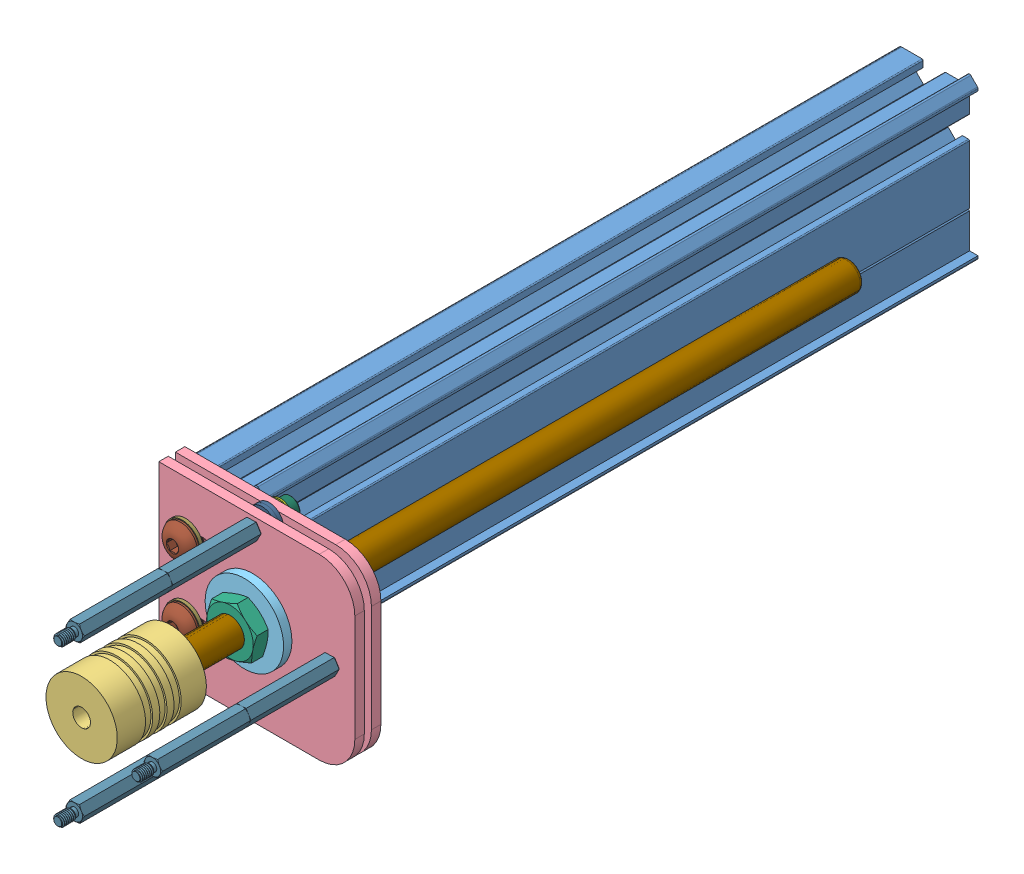
SolidWorks assembly S2_Zaxis_500, configuration Default. Lengths in mm.
Overall size (63.97 54.77 264.94).
47 component instances, 18 part files, 97 mates.
Components (placement in the parent):
- 25142-07-1: 25142-07 [Default] at origin size (22.38 45.94 200)
- 26016-01-1: 26016-01 [Default] at (-6.4 10 -90) x (0 1 0) z (0 0 1) size (10 1.6 15)
- 26016-01-2: 26016-01 [Default] at (-6.4 10 29.5) x (0 1 0) z (0 0 1) size (10 1.6 15)
- 26016-01-3: 26016-01 [Default] at (-6.4 -10 -90) x (0 1 0) z (0 0 1) size (10 1.6 15)
- 26016-01-4: 26016-01 [Default] at (-6.4 -10 29.5) x (0 1 0) z (0 0 1) size (10 1.6 15)
- 25772-02-1: 25772-02 [Default] at (18.85 0 157.9705) x (-0.547932 -0.836523 0) z (0 0 -1) size (20 20 25)
- z-mount_plates-1: z-mount_plates [Default] at (2.5 0 102.6568) size (55 50 2.66)
- z-mount_plates-2: z-mount_plates [Default] at (2.5 0 107.3137) size (55 50 2.66)
- 30169-01-1: 30169-01 [Default] at (18.85 0 112.3137) x (1 -0.000065 0) z (0 0 -1) size (25 25 7)
- 90695A040-1: 90695A040 [Default] at (18.85 0 114.3137) x (-0.665272 -0.746601 0) z (0.746601 -0.665272 0) size (13 4.47 15.01)
- 90695A040-2: 90695A040 [Default] at (18.85 0 103.3137) x (0.698752 0.715364 0) z (0.715364 -0.698752 0) size (13 4.47 15.01)
- 25287-03-1: 25287-03 [Default] at (18.85 21.9203 102.2068) x (0.999998 -0.002105 0) z (0 0 -1) size (7 7 0.45)
- 25287-03-2: 25287-03 [Default] at (40.7703 0 102.2068) x (0.999998 -0.002105 0) z (0 0 -1) size (7 7 0.45)
- 25287-03-3: 25287-03 [Default] at (18.85 -21.9203 102.2068) x (0.999998 -0.002105 0) z (0 0 -1) size (7 7 0.45)
- z-axis shim-1: z-axis shim [Default] at (0 0 100) x (0 1 0) z (0 0 1) size (40 20 2.66)
- SM-H05-1: SM-H05 [Default] at (18.85 0 -57.5045) x (0.600975 0.799267 0) z (0 0 1) size (8 8 200.01)
- 492-1101-ND-1: 492-1101-ND [Default] at (18.85 21.9203 106.3137) x (0.918344 -0.395784 0) z (0 0 1) size (8 8 1)
- 492-1101-ND-2: 492-1101-ND [Default] at (40.7703 0 106.3137) x (1 -0.000065 0) z (0 0 1) size (8 8 1)
- 492-1101-ND-3: 492-1101-ND [Default] at (18.85 -21.9203 106.3137) x (1 -0.000065 0) z (0 0 1) size (8 8 1)
- 91239A233-1: 91239A233 [Default] at (0 -10 90.8705) x (-0.018677 0.999826 0) z (0 0 -1) size (9.5 9.5 22.91)
- 25287-02-1: 25287-02 [Default] at (0 -10 110.8705) x (-0.018677 0.999826 0) z (0 0 1) size (10 10 0.9)
- 91239A233-2: 91239A233 [Default] at (0 10 90.8705) x (-0.018677 0.999826 0) z (0 0 -1) size (9.5 9.5 22.91)
- 25287-02-2: 25287-02 [Default] at (0 10 110.8705) x (-0.018677 0.999826 0) z (0 0 1) size (10 10 0.9)
- PSM5-01MM-1: PSM5-01MM [Default] at (0 10 106.3137) x (-0.941883 0.335942 0) z (0 0 -1) size (10 10 1)
- PSM5-01MM-2: PSM5-01MM [Default] at (0 -10 105.3137) x (1 -0.000065 0) z (0 0 1) size (10 10 1)
- PSBS-50-1: PSBS-50 [Default] at (18.85 21.9203 149.8205) x (0 0 1) z (0.847933 0.530103 0) size (54.97 5.2 4.5)
- PSBS-50-2: PSBS-50 [Default] at (18.85 -21.9203 149.8205) x (0 0 1) z (0.847933 0.530103 0) size (54.97 5.2 4.5)
- PSBS-50-3: PSBS-50 [Default] at (40.7703 0 149.8205) x (0 0 1) z (0.847933 0.530103 0) size (54.97 5.2 4.5)
- 25285-10-1: 25285-10 [Default] at (18.85 21.9203 114.2068) x (1 -0.000065 0) z (0 0 1) size (5.5 5.5 15.14)
- 25285-10-2: 25285-10 [Default] at (40.7703 0 114.2068) x (1 -0.000065 0) z (0 0 1) size (5.5 5.5 15.14)
- 25285-10-3: 25285-10 [Default] at (18.85 -21.9203 114.2068) x (1 -0.000065 0) z (0 0 1) size (5.5 5.5 15.14)
- PSM5-01MM-3: PSM5-01MM [Default] at (0 10 106.3137) x (-0.91721 -0.398405 0) z (0 0 1) size (10 10 1)
- PSM5-01MM-4: PSM5-01MM [Default] at (0 -10 106.3137) x (-0.91721 -0.398405 0) z (0 0 1) size (10 10 1)
- 492-1101-ND-4: 492-1101-ND [Default] at (18.85 21.9203 105.3137) x (0.69206 -0.72184 0) z (0 0 1) size (8 8 1)
- 492-1101-ND-5: 492-1101-ND [Default] at (40.7703 0 106.3137) x (0.914241 0.405172 0) z (0 0 -1) size (8 8 1)
- 492-1101-ND-6: 492-1101-ND [Default] at (18.85 -21.9203 106.3137) x (0.914241 0.405172 0) z (0 0 -1) size (8 8 1)
- 91290A272-1: 91290A272 [Default] at (152.9795 421.0336 165.2742) x (-0.956811 0.027475 0.289409) z (-0.289409 0.004064 -0.957197) (suppressed, hidden)
- 91290A272-6: 91290A272 [Default] at (88.3739 418.8513 182.2519) x (-0.956811 0.027475 0.289409) z (-0.289409 0.004064 -0.957197) (suppressed, hidden)
- 9714K630-1: 9714K630 [Default] at (18.85 0 105.2817) x (-0.456655 -0.889644 0) z (-0.889644 0.456655 0) size (30.59 5.44 32.38)
- 25287-02-3: 25287-02 [Default] at (-13.56 -10 -90) x (0 0.90826 -0.418406) z (-1 0 0) size (10 10 0.9)
- 25286-01-1: 25286-01 [Default] at (-3.56 -10 -90) x (0 0.955266 -0.295749) z (1 0 0) size (9.5 9.5 12.91)
- 25287-02-4: 25287-02 [Default] at (-13.56 -10 29.5) x (0 0.90826 -0.418406) z (-1 0 0) size (10 10 0.9)
- 25286-01-2: 25286-01 [Default] at (-3.56 -10 29.5) x (0 0.955266 -0.295749) z (1 0 0) size (9.5 9.5 12.91)
- 25287-02-5: 25287-02 [Default] at (-13.56 10 -90) x (0 0.90826 -0.418406) z (-1 0 0) size (10 10 0.9)
- 25286-01-3: 25286-01 [Default] at (-3.56 10 -90) x (0 0.955266 -0.295749) z (1 0 0) size (9.5 9.5 12.91)
- 25287-02-6: 25287-02 [Default] at (-13.56 10 29.5) x (0 0.90826 -0.418406) z (-1 0 0) size (10 10 0.9)
- 25286-01-4: 25286-01 [Default] at (-3.56 10 29.5) x (0 0.955266 -0.295749) z (1 0 0) size (9.5 9.5 12.91)
Mates (geometry in assembly coordinates):
- Coincident51: coincident anti-aligned: plane of 25142-07-1 through (-8 -16 0) normal (1 0 0); plane of 26016-01-3 through (-8 -10 -90) normal (-1 0 0)
- Coincident52: coincident anti-aligned: plane of 25142-07-1 through (-8 -16 0) normal (1 0 0); plane of 26016-01-4 through (-8 -10 29.5) normal (-1 0 0)
- Coincident53: coincident anti-aligned: plane of 25142-07-1 through (-8 13 0) normal (1 0 0); plane of 26016-01-2 through (-8 10 29.5) normal (-1 0 0)
- Coincident54: coincident anti-aligned: plane of 25142-07-1 through (-8 13 0) normal (1 0 0); plane of 26016-01-1 through (-8 10 -90) normal (-1 0 0)
- Coincident55: coincident aligned: plane of 26016-01-1 through (-6.4 15 -97.5) normal (0 0 -1); plane of 26016-01-3 through (-6.4 -5 -97.5) normal (0 0 -1)
- Coincident57: coincident aligned: plane of 25142-07-1 through (0 10 0) normal (0 1 0); plane of 26016-01-1
- Coincident58: coincident aligned: plane of 25142-07-1 through (0 10 0) normal (0 1 0); plane of 26016-01-2
- Coincident59: coincident aligned: plane of 25142-07-1 through (0 -10 0) normal (0 1 0); plane of 26016-01-3
- Coincident60: coincident aligned: plane of 25142-07-1 through (0 -10 0) normal (0 1 0); plane of 26016-01-4
- Distance1: distance = 2.5 mm aligned: plane of 25142-07-1 through (0.3057 0.8501 -100) normal (0 0 -1); plane of 26016-01-1 through (-6.4 15 -97.5) normal (0 0 -1)
- Concentric44: concentric anti-aligned: cylinder of z-mount_plates-2 through (18.85 0 107.3137) axis (0 0 1) radius 11; cylinder of 30169-01-1 through (18.85 0 112.3137) axis (0 0 -1) radius 11
- Concentric45: concentric anti-aligned: cylinder of z-mount_plates-2 through (0 -10 107.3137) axis (0 0 1) radius 2.75; cylinder of 91239A233-1 through (0 -10 113.6205) axis (0 0 -1) radius 4.75
- Concentric46: concentric anti-aligned: cylinder of z-mount_plates-2 through (0 10 107.3137) axis (0 0 1) radius 2.75; cylinder of 91239A233-2 through (0 10 113.6205) axis (0 0 -1) radius 4.75
- Concentric47: concentric anti-aligned: cylinder of 91239A233-2 through (0 10 113.6205) axis (0 0 -1) radius 4.75; cylinder of 25287-02-2 through (0 10 109.9705) axis (0 0 1) radius 5
- Concentric48: concentric anti-aligned: cylinder of 91239A233-1 through (0 -10 113.6205) axis (0 0 -1) radius 4.75; cylinder of 25287-02-1 through (0 -10 109.9705) axis (0 0 1) radius 5
- Concentric49: concentric aligned: cylinder of z-mount_plates-1 through (0 -10 102.6568) axis (0 0 1) radius 2.75; cylinder of z-mount_plates-2 through (0 -10 107.3137) axis (0 0 1) radius 2.75
- Concentric50: concentric aligned: cylinder of z-mount_plates-1 through (0 10 102.6568) axis (0 0 1) radius 2.75; cylinder of z-mount_plates-2 through (0 10 107.3137) axis (0 0 1) radius 2.75
- Concentric51: concentric aligned: cylinder of PSM5-01MM-2 through (0 -10 105.3137) axis (0 0 1) radius 5; cylinder of PSM5-01MM-4 through (0 -10 106.3137) axis (0 0 1) radius 5
- Concentric52: concentric anti-aligned: cylinder of PSM5-01MM-1 through (0 10 106.3137) axis (0 0 -1) radius 5; cylinder of PSM5-01MM-3 through (0 10 106.3137) axis (0 0 1) radius 5
- Concentric53: concentric anti-aligned: cylinder of 492-1101-ND-3 through (18.85 -21.9203 106.3137) axis (0 0 1) radius 4; cylinder of 492-1101-ND-6 through (18.85 -21.9203 106.3137) axis (0 0 -1) radius 4
- Concentric54: concentric anti-aligned: cylinder of 492-1101-ND-2 through (40.7703 0 106.3137) axis (0 0 1) radius 4; cylinder of 492-1101-ND-5 through (40.7703 0 106.3137) axis (0 0 -1) radius 4
- Concentric55: concentric aligned: cylinder of 492-1101-ND-1 through (18.85 21.9203 106.3137) axis (0 0 1) radius 4; cylinder of 492-1101-ND-4 through (18.85 21.9203 105.3137) axis (0 0 1) radius 4
- Concentric56: concentric anti-aligned: cylinder of 25287-03-3 through (18.85 -21.9203 102.6568) axis (0 0 -1) radius 3.5; cylinder of 25285-10-3 through (18.85 -21.9203 99.2068) axis (0 0 1) radius 2.75
- Concentric57: concentric anti-aligned: cylinder of 25287-03-2 through (40.7703 0 102.6568) axis (0 0 -1) radius 3.5; cylinder of 25285-10-2 through (40.7703 0 99.2068) axis (0 0 1) radius 2.75
- Concentric58: concentric anti-aligned: cylinder of 25287-03-1 through (18.85 21.9203 102.6568) axis (0 0 -1) radius 3.5; cylinder of 25285-10-1 through (18.85 21.9203 99.2068) axis (0 0 1) radius 2.75
- Concentric59: concentric anti-aligned: cylinder of 25285-10-2 through (40.7703 0 99.2068) axis (0 0 1) radius 2.75; cylinder of 492-1101-ND-5 through (40.7703 0 106.3137) axis (0 0 -1) radius 1.5
- Concentric60: concentric aligned: cylinder of 25285-10-1 through (18.85 21.9203 99.2068) axis (0 0 1) radius 2.75; cylinder of 492-1101-ND-4 through (18.85 21.9203 105.3137) axis (0 0 1) radius 1.5
- Concentric61: concentric anti-aligned: cylinder of 25285-10-3 through (18.85 -21.9203 99.2068) axis (0 0 1) radius 2.75; cylinder of 492-1101-ND-6 through (18.85 -21.9203 106.3137) axis (0 0 -1) radius 1.5
- Coincident64: coincident anti-aligned: plane of 25287-03-3 through (18.85 -21.9203 102.2068) normal (0 0 -1); plane of 25285-10-3 through (18.85 -21.9203 102.2068) normal (0 0 1)
- Coincident65: coincident anti-aligned: plane of 25287-03-2 through (40.7703 0 102.2068) normal (0 0 -1); plane of 25285-10-2 through (40.7703 0 102.2068) normal (0 0 1)
- Coincident66: coincident anti-aligned: plane of 25287-03-1 through (18.85 21.9203 102.2068) normal (0 0 -1); plane of 25285-10-1 through (18.85 21.9203 102.2068) normal (0 0 1)
- Concentric62: concentric aligned: cylinder of z-mount_plates-1 through (18.85 0 102.6568) axis (0 0 1) radius 11; circle of 90695A040-2
- Concentric63: concentric aligned: cylinder of z-mount_plates-2 through (18.85 0 107.3137) axis (0 0 1) radius 11; circle of 90695A040-1
- Concentric64: concentric anti-aligned: cylinder of z-mount_plates-2 through (18.85 -21.9203 107.3137) axis (0 0 1) radius 1.75; cylinder of PSBS-50-2 through (18.85 -21.9203 149.8205) axis (0 0 -1) radius 1.1727
- Concentric65: concentric anti-aligned: cylinder of z-mount_plates-2 through (40.7703 0 107.3137) axis (0 0 1) radius 1.75; cylinder of PSBS-50-3 through (40.7703 0 149.8205) axis (0 0 -1) radius 1.1727
- Concentric66: concentric anti-aligned: cylinder of z-mount_plates-2 through (18.85 21.9203 107.3137) axis (0 0 1) radius 1.75; cylinder of PSBS-50-1 through (18.85 21.9203 149.8205) axis (0 0 -1) radius 1.1727
- Concentric67: concentric anti-aligned: cylinder of 30169-01-1 through (18.85 0 112.3137) axis (0 0 -1) radius 4; cylinder of SM-H05-1 through (18.85 0 -57.5045) axis (0 0 1) radius 4
- Coincident67: coincident anti-aligned: plane of 492-1101-ND-2 through (40.7703 0 106.3137) normal (0 0 -1); plane of 492-1101-ND-5 through (40.7703 0 106.3137) normal (0 0 1)
- Coincident68: coincident anti-aligned: plane of 492-1101-ND-3 through (18.85 -21.9203 106.3137) normal (0 0 -1); plane of 492-1101-ND-6 through (18.85 -21.9203 106.3137) normal (0 0 1)
- Coincident69: coincident anti-aligned: plane of PSM5-01MM-1 through (0 10 106.3137) normal (0 0 1); plane of PSM5-01MM-3 through (0 10 106.3137) normal (0 0 -1)
- Coincident70: coincident anti-aligned: plane of 492-1101-ND-1 through (18.85 21.9203 106.3137) normal (0 0 -1); plane of 492-1101-ND-4 through (18.85 21.9203 106.3137) normal (0 0 1)
- Coincident71: coincident anti-aligned: plane of PSM5-01MM-2 through (0 -10 106.3137) normal (0 0 1); plane of PSM5-01MM-4 through (0 -10 106.3137) normal (0 0 -1)
- Concentric68: concentric aligned: cylinder of 25142-07-1 through (0 -10 100) axis (0 0 -1) radius 2.5; cylinder of z-axis shim-1 through (0 -10 102.6568) axis (0 0 -1) radius 2.75
- Concentric69: concentric aligned: cylinder of 25142-07-1 through (0 10 100) axis (0 0 -1) radius 2.5; cylinder of z-axis shim-1 through (0 10 102.6568) axis (0 0 -1) radius 2.75
- Coincident72: coincident anti-aligned: plane of 25142-07-1 through (0 0 100) normal (0 0 1); plane of z-axis shim-1 through (-0.1617 0 100) normal (0 0 -1)
- Coincident73: coincident anti-aligned: plane of 91239A233-1 through (0 -10 110.8705) normal (0 0 -1); plane of 25287-02-1 through (0 -10 110.8705) normal (0 0 1)
- Coincident74: coincident anti-aligned: plane of 91239A233-2 through (0 10 110.8705) normal (0 0 -1); plane of 25287-02-2 through (0 10 110.8705) normal (0 0 1)
- Coincident75: coincident anti-aligned: plane of z-mount_plates-2 through (20 0 109.9705) normal (0 0 1); plane of 25287-02-2 through (0 10 109.9705) normal (0 0 -1)
- Coincident76: coincident anti-aligned: plane of z-mount_plates-2 through (20 0 109.9705) normal (0 0 1); plane of 25287-02-1 through (0 -10 109.9705) normal (0 0 -1)
- Concentric70: concentric anti-aligned: cylinder of 25772-02-1 through (18.85 0 157.9705) axis (0 0 -1) radius 2.5; cylinder of SM-H05-1 through (18.85 0 -57.5045) axis (0 0 1) radius 4
- Coincident77: coincident anti-aligned: plane of z-mount_plates-2 through (20 0 109.9705) normal (0 0 1); plane of PSBS-50-2 through (17.8069 -23.8832 109.9705) normal (0 0 -1)
- Coincident78: coincident anti-aligned: plane of z-mount_plates-2 through (20 0 109.9705) normal (0 0 1); plane of PSBS-50-3 through (39.7272 -1.9629 109.9705) normal (0 0 -1)
- Coincident79: coincident anti-aligned: plane of z-mount_plates-2 through (20 0 109.9705) normal (0 0 1); plane of PSBS-50-1 through (17.8069 19.9574 109.9705) normal (0 0 -1)
- Coincident80: coincident anti-aligned: plane of z-mount_plates-2 through (20 0 107.3137) normal (0 0 -1); plane of 492-1101-ND-1 through (18.85 21.9203 107.3137) normal (0 0 1)
- Coincident81: coincident anti-aligned: plane of z-mount_plates-2 through (20 0 107.3137) normal (0 0 -1); plane of PSM5-01MM-3 through (0 10 107.3137) normal (0 0 1)
- Coincident82: coincident anti-aligned: plane of z-mount_plates-2 through (20 0 107.3137) normal (0 0 -1); plane of PSM5-01MM-4 through (0 -10 107.3137) normal (0 0 1)
- Coincident86: coincident anti-aligned: plane of z-mount_plates-2 through (20 0 107.3137) normal (0 0 -1); plane of 492-1101-ND-2 through (40.7703 0 107.3137) normal (0 0 1)
- Coincident87: coincident anti-aligned: plane of z-mount_plates-1 through (20 0 102.6568) normal (0 0 -1); plane of z-axis shim-1 through (-0.1617 0 102.6568) normal (0 0 1)
- Coincident88: coincident anti-aligned: plane of z-mount_plates-2 through (20 0 107.3137) normal (0 0 -1); plane of 492-1101-ND-3 through (18.85 -21.9203 107.3137) normal (0 0 1)
- Coincident89: coincident anti-aligned: plane of z-mount_plates-1 through (20 0 105.3137) normal (0 0 1); plane of 492-1101-ND-5 through (40.7703 0 105.3137) normal (0 0 -1)
- Concentric71: concentric aligned: cylinder of z-mount_plates-1 through (40.7703 0 102.6568) axis (0 0 1) radius 1.75; cylinder of 25285-10-2 through (40.7703 0 99.2068) axis (0 0 1) radius 2.75
- Concentric72: concentric aligned: cylinder of z-mount_plates-1 through (18.85 -21.9203 102.6568) axis (0 0 1) radius 1.75; cylinder of 25285-10-3 through (18.85 -21.9203 99.2068) axis (0 0 1) radius 2.75
- Concentric73: concentric aligned: cylinder of z-mount_plates-1 through (18.85 21.9203 102.6568) axis (0 0 1) radius 1.75; cylinder of 25285-10-1 through (18.85 21.9203 99.2068) axis (0 0 1) radius 2.75
- Coincident92: coincident anti-aligned: plane of z-mount_plates-1 through (20 0 102.6568) normal (0 0 -1); plane of 25287-03-2 through (40.7703 0 102.6568) normal (0 0 1)
- Coincident93: coincident anti-aligned: plane of z-mount_plates-1 through (20 0 102.6568) normal (0 0 -1); plane of 25287-03-1 through (18.85 21.9203 102.6568) normal (0 0 1)
- Coincident95: coincident anti-aligned: plane of 30169-01-1 through (18.85 0 105.3137) normal (0 0 -1); plane of 90695A040-2 through (13.4808 5.2445 105.3137) normal (0 0 1)
- Coincident96: coincident anti-aligned: plane of 30169-01-1 through (18.85 0 112.3137) normal (0 0 1); plane of 90695A040-1 through (13.2463 4.9932 112.3137) normal (0 0 -1)
- Coincident97: coincident anti-aligned: plane of z-mount_plates-1 through (20 0 105.3137) normal (0 0 1); plane of 30169-01-1 through (18.85 0 105.3137) normal (0 0 -1)
- Tangent3: tangent: plane of z-mount_plates-2 through (20 0 107.3137) normal (0 0 -1); face of 9714K630-1
- Coincident98: coincident anti-aligned: plane of 25772-02-1 through (18.85 0 142.4955) normal (0 0 -1); plane of SM-H05-1 through (18.85 0 142.4955) normal (0 0 1)
- Distance3: distance = 2 mm aligned: plane of 25772-02-1 through (18.85 0 157.9705) normal (0 0 1); plane of PSBS-50-2 through (20.2272 -24.1233 159.9705) normal (0 0 1)
- Coincident100: coincident anti-aligned: plane of z-mount_plates-1 through (20 0 102.6568) normal (0 0 -1); plane of 25287-03-3 through (18.85 -21.9203 102.6568) normal (0 0 1)
- Concentric74: concentric anti-aligned: cylinder of 91239A233-2 through (0 10 113.6205) axis (0 0 -1) radius 4.75; cylinder of PSM5-01MM-3 through (0 10 106.3137) axis (0 0 1) radius 5
- Concentric75: concentric anti-aligned: cylinder of 91239A233-1 through (0 -10 113.6205) axis (0 0 -1) radius 4.75; cylinder of PSM5-01MM-4 through (0 -10 106.3137) axis (0 0 1) radius 5
- Concentric76: concentric aligned: cylinder of 25142-07-1 through (0 -10 100) axis (0 0 -1) radius 2.5; cylinder of 91239A233-1 through (0 -10 113.6205) axis (0 0 -1) radius 4.75
- Concentric77: concentric aligned: cylinder of 25142-07-1 through (0 10 100) axis (0 0 -1) radius 2.5; cylinder of 91239A233-2 through (0 10 113.6205) axis (0 0 -1) radius 4.75
- Concentric78: concentric anti-aligned: cylinder of SM-H05-1 through (18.85 0 -57.5045) axis (0 0 1) radius 4; line of 9714K630-1 through (18.85 0 109.2873) axis (0 0 -1)
- Coincident103: coordinate: point of 25142-07-1; point of assembly
- Concentric40: concentric anti-aligned: cylinder of 25287-02-3 through (-12.66 -10 -90) axis (-1 0 0) radius 5; cylinder of 25286-01-1 through (-16.31 -10 -90) axis (1 0 0) radius 4.75
- Coincident42: coincident anti-aligned: plane of 25287-02-3 through (-13.56 -10 -90) normal (-1 0 0); plane of 25286-01-1 through (-13.56 -10 -90) normal (1 0 0)
- Coincident43: coincident anti-aligned: plane of 25287-02-4 through (-13.56 -10 29.5) normal (-1 0 0); plane of 25286-01-2 through (-13.56 -10 29.5) normal (1 0 0)
- Concentric41: concentric anti-aligned: cylinder of 25287-02-4 through (-12.66 -10 29.5) axis (-1 0 0) radius 5; cylinder of 25286-01-2 through (-16.31 -10 29.5) axis (1 0 0) radius 4.75
- Coincident44: coincident anti-aligned: plane of 25287-02-5 through (-13.56 10 -90) normal (-1 0 0); plane of 25286-01-3 through (-13.56 10 -90) normal (1 0 0)
- Concentric42: concentric anti-aligned: cylinder of 25287-02-5 through (-12.66 10 -90) axis (-1 0 0) radius 5; cylinder of 25286-01-3 through (-16.31 10 -90) axis (1 0 0) radius 4.75
- Concentric43: concentric anti-aligned: cylinder of 25287-02-6 through (-12.66 10 29.5) axis (-1 0 0) radius 5; cylinder of 25286-01-4 through (-16.31 10 29.5) axis (1 0 0) radius 4.75
- Coincident45: coincident anti-aligned: plane of 25287-02-6 through (-13.56 10 29.5) normal (-1 0 0); plane of 25286-01-4 through (-13.56 10 29.5) normal (1 0 0)
- Concentric16: concentric anti-aligned: cylinder of 25286-01-3 through (-16.31 10 -90) axis (1 0 0) radius 4.75; cylinder of 26016-01-1 through (-6.4 10 -90) axis (-1 0 0) radius 2.5
- Concentric79: concentric anti-aligned: cylinder of 26016-01-4 through (-6.4 -10 29.5) axis (-1 0 0) radius 2.5; cylinder of 25286-01-2 through (-16.31 -10 29.5) axis (1 0 0) radius 4.75
- Concentric80: concentric anti-aligned: cylinder of 26016-01-2 through (-6.4 10 29.5) axis (-1 0 0) radius 2.5; cylinder of 25286-01-4 through (-16.31 10 29.5) axis (1 0 0) radius 4.75
- Concentric81: concentric anti-aligned: cylinder of 26016-01-3 through (-6.4 -10 -90) axis (-1 0 0) radius 2.5; cylinder of 25286-01-1 through (-16.31 -10 -90) axis (1 0 0) radius 4.75
- Concentric82: concentric anti-aligned: cylinder of 26016-01-1 through (-6.4 10 -90) axis (-1 0 0) radius 2.5; cylinder of 25286-01-3 through (-16.31 10 -90) axis (1 0 0) radius 4.75
- Coincident104: coincident aligned: plane of 26016-01-2 through (-6.4 15 22) normal (0 0 -1); plane of 26016-01-4 through (-6.4 -5 22) normal (0 0 -1)
- Coincident105: coincident aligned: plane of 25287-02-3 through (-12.66 -10 -90) normal (1 0 0); plane of 25287-02-5 through (-12.66 10 -90) normal (1 0 0)
- Coincident106: coincident aligned: plane of 25287-02-3 through (-12.66 -10 -90) normal (1 0 0); plane of 25287-02-4 through (-12.66 -10 29.5) normal (1 0 0)
- Coincident107: coincident aligned: plane of 25287-02-3 through (-12.66 -10 -90) normal (1 0 0); plane of 25287-02-6 through (-12.66 10 29.5) normal (1 0 0)
- Distance4: distance = 2.66 mm anti-aligned: plane of 25287-02-3 through (-12.66 -10 -90) normal (1 0 0); plane of 25142-07-1 through (-10 6.7 0) normal (-1 0 0)
- Distance5: distance = 110 mm: cylinder of 25286-01-3 through (-16.31 10 -90) axis (1 0 0) radius 4.75; cylinder of 25286-01-4 through (-16.31 10 29.5) axis (1 0 0) radius 4.75
